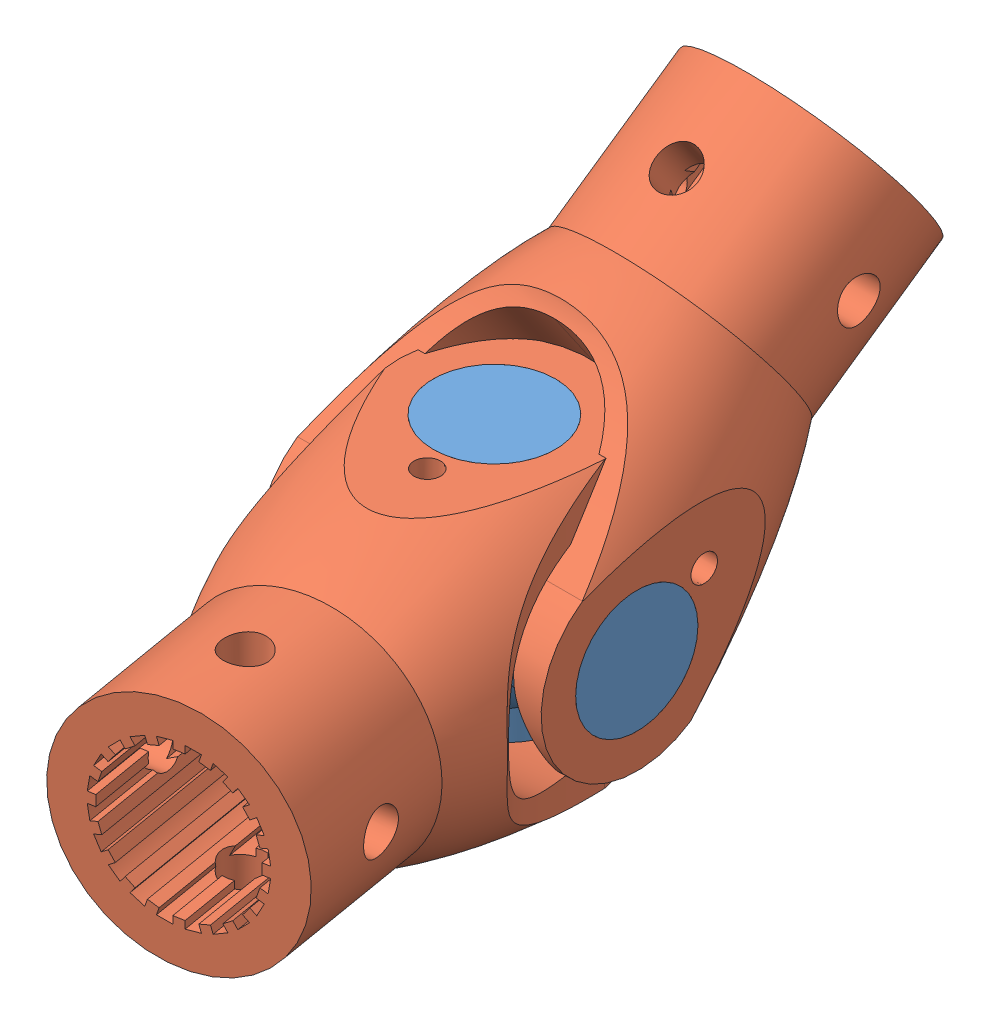
SolidWorks assembly Steering Unversal Joint, configuration Default. Lengths in mm.
Overall size (50.03 66.37 98.25).
3 component instances, 2 part files, 4 mates.
Components (placement in the parent):
- Universal Joint Trunnion-1: Universal Joint Trunnion [Default] at origin size (34.02 34.02 14.61)
- Universal Joint Carrier-1: Universal Joint Carrier [Default] at (7.6573 -0.0058 45.3318) x (0 1 0) z (0.166556 0 0.986032) size (41.04 41.04 57.4)
- Universal Joint Carrier-2: Universal Joint Carrier [Default] at (-0.0058 26.092 -37.8526) x (1 0 0) z (0 0.567538 -0.823347) size (41.04 41.04 57.4)
Mates (geometry in assembly coordinates):
- Coincident1: coincident aligned: plane of Universal Joint Trunnion-1 through (0 17.0122 0) normal (0 1 0); plane of Universal Joint Carrier-1 through (-125.3249 17.0122 1.3121) normal (0 1 0)
- Concentric1: concentric anti-aligned: cylinder of Universal Joint Trunnion-1 through (0 17.0122 0) axis (0 -1 0) radius 7.3025; cylinder of Universal Joint Carrier-1 through (0 -20.5798 0) axis (0 1 0) radius 7.3025
- Coincident2: coincident aligned: plane of Universal Joint Trunnion-1 through (17.0122 0 0) normal (1 0 0); plane of Universal Joint Carrier-2 through (17.0122 -113.0369 -54.1361) normal (1 0 0)
- Concentric2: concentric anti-aligned: cylinder of Universal Joint Trunnion-1 through (17.0122 0 0) axis (-1 0 0) radius 7.3025; cylinder of Universal Joint Carrier-2 through (-20.5798 0 0) axis (1 0 0) radius 7.3025
